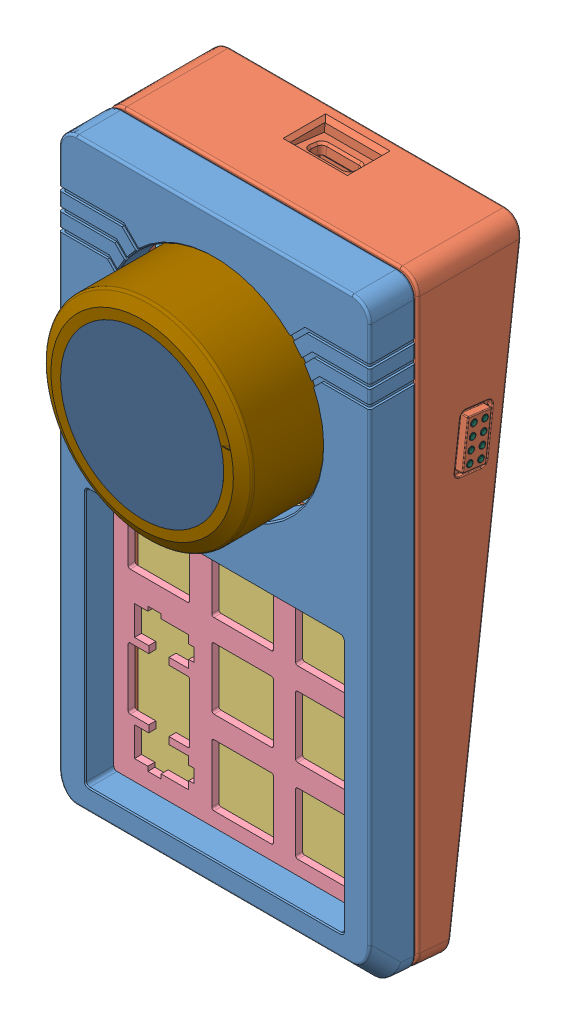
SolidWorks assembly 00-装配体 旋钮扩展, configuration 默认. Lengths in mm.
Overall size (76.26 142.75 71.45).
19 component instances, 17 part files, 22 mates.
Components (placement in the parent):
- 01 零件 旋钮扩展上盖-1: 01 零件 旋钮扩展上盖 [默认] at origin size (70.5 136.95 11.4)
- 02-零件 旋钮扩展底壳-1: 02-零件 旋钮扩展底壳 [默认] at (70.5 1.7565 0) x (-1 0 0) z (0 0 -1) size (72.2 137.62 26.75)
- 04-零件 旋钮扩展按键PCB板-1: 04-零件 旋钮扩展按键PCB板 [默认] at (34.7996 31.8269 -1.2) size (57.5 71.01 1.2)
- 03-零件 旋钮扩展定位板-1: 03-零件 旋钮扩展定位板 [默认] at (15.5008 11.1842 3.4) x (1 0 0) z (0 -1 0) size (64.5 1.6 69.5)
- 00-装配体 旋钮部分-1: 00-装配体 旋钮部分 [默认] at (35.25 104 -1.2) x (-1 0 0) z (0 1 0) size (76.26 54.3 76.26)
  - 01-零件 PCB板-1: 01-零件 PCB板 [默认] at origin size (50 1 50)
  - 02-零件 电机底座-1: 02-零件 电机底座 [默认] at (0 6.2 0) size (46.19 23 52.91)
  - 03-零件 电机-1: 03-零件 电机 [默认] at (0 4.58 0) x (0 0 1) z (-1 0 0) size (47.53 47.1 35.44)
  - 04-零件 电机上罩-1: 04-零件 电机上罩 [默认] at (0 10.7 0) x (0.707107 0 0.707107) z (-0.707107 0 0.707107) size (56.5 12.14 51.36)
  - 05-零件 旋钮上外壳-1: 05-零件 旋钮上外壳 [默认] at (0 2.8 0) x (0.965926 0 -0.258819) z (0.258819 0 0.965926) size (47 26.2 47)
  - 06-零件 旋钮玻璃-1: 06-零件 旋钮玻璃 [默认] at (0 28 0) size (37 1 37)
  - 07-零件 6x6x5轻触开关-1: 07-零件 6x6x5轻触开关 [默认] at (0 0 -10) x (-1 0 0) z (0 0 1) size (6 5 6)
  - 零件 TFTLCD支撑圈-1: 零件 TFTLCD支撑圈 [默认] at (0 19 0) size (11.21 5.4 12)
  - 零件 PCB-TFTLCD-1: 零件 PCB-TFTLCD [默认] at (0 24 0) x (1 0 0) z (0 1 0) size (38.77 35.97 1)
  - 零件 TFT LCD 1.28inch-1: 零件 TFT LCD 1.28inch [默认] at (0 25.3 0) size (38.6 1.9 35.6)
- 08-Q零件 顶针2x4pin 母座-1: 08-Q零件 顶针2x4pin 母座 [默认] at (68.9 94.1579 -9.0911) x (0 0.992546 -0.121869) z (0 0.121869 0.992546) size (10.2 6.8 5)
- 09-Q零件 顶针2x4pin 公头-1: 09-Q零件 顶针2x4pin 公头 [默认] at (1.7 104.2819 -10.3341) x (0 -0.992546 0.121869) z (0 0.121869 0.992546) size (10.2 6.85 5)
- 06-Q零件 磁铁 20x3-1: 06-Q零件 磁铁 20x3 [默认] at (4 118.4896 -10.0636) x (0 0 1) z (-1 0 0) size (20 20 3)
- 06-Q零件 磁铁 20x3-2: 06-Q零件 磁铁 20x3 [默认] at (66.5 118.4896 -10.0636) x (0 0 -1) z (1 0 0) size (20 20 3)
Mates (geometry in assembly coordinates):
- 重合28: coincident anti-aligned: plane of 01 零件 旋钮扩展上盖-1 through (70.5 0 0) normal (0 0 -1); plane of 02-零件 旋钮扩展底壳-1 through (70.5 1.7565 0) normal (0 0 1)
- 重合29: coincident aligned: plane of 01 零件 旋钮扩展上盖-1 through (70.5 137 0) normal (0 1 0); plane of 02-零件 旋钮扩展底壳-1 through (0 137 0) normal (0 1 0)
- 重合30: coincident aligned: plane of 01 零件 旋钮扩展上盖-1 through (0 0 0) normal (-1 0 0); plane of 02-零件 旋钮扩展底壳-1 through (0 1.7565 0) normal (-1 0 0)
- 重合35: coincident anti-aligned: plane of 02-零件 旋钮扩展底壳-1 through (70.5 1.7565 -1.2) normal (0 0 1); plane of 04-零件 旋钮扩展按键PCB板-1 through (34.7996 31.8269 -1.2) normal (0 0 -1)
- 距离2: distance = 0.5 mm anti-aligned: plane of 02-零件 旋钮扩展底壳-1 through (6 1.7565 -151.4076) normal (1 0 0); plane of 04-零件 旋钮扩展按键PCB板-1 through (6.5 72.4203 0) normal (-1 0 0)
- 距离3: distance = 0.5 mm anti-aligned: plane of 02-零件 旋钮扩展底壳-1 through (70.5 5.9125 -151.4076) normal (0 1 0); plane of 04-零件 旋钮扩展按键PCB板-1 through (6.5 6.4125 0) normal (0 -1 0)
- 重合41: coincident anti-aligned: plane of 02-零件 旋钮扩展底壳-1 through (66.35 129.2 3.4) normal (0 0 1); plane of 03-零件 旋钮扩展定位板-1 through (4.15 7.7125 3.4) normal (0 0 -1)
- 重合42: coincident aligned: line of 02-零件 旋钮扩展底壳-1 through (3 70.8831 3.4) axis (0 -1 0); line of 03-零件 旋钮扩展定位板-1 through (3 71.9125 3.4) axis (0 -1 0)
- 重合43: coincident aligned: line of 02-零件 旋钮扩展底壳-1 through (7.8 2.9125 3.4) axis (1 0 0); line of 03-零件 旋钮扩展定位板-1 through (7.8 2.9125 3.4) axis (1 0 0)
- 重合44: coincident anti-aligned: plane of 02-零件 旋钮扩展底壳-1 through (70.5 1.7565 -1.2) normal (0 0 1); plane of 00-装配体 旋钮部分-1/01-零件 PCB板-1 through (35.25 104 -1.2) normal (0 0 -1)
- 同心1: concentric anti-aligned: circle of 01 零件 旋钮扩展上盖-1; circle of 00-装配体 旋钮部分-1/05-零件 旋钮上外壳-1
- 平行1: parallel: plane of 02-零件 旋钮扩展底壳-1 through (70.5 131 -151.4076) normal (0 -1 0); line of 00-装配体 旋钮部分-1/01-零件 PCB板-1 through (60.25 129 -0.2) axis (-1 0 0)
- 重合51: coincident anti-aligned: plane of 02-零件 旋钮扩展底壳-1 through (68.9 1.7565 0) normal (-1 0 0); plane of 08-Q零件 顶针2x4pin 母座-1 through (68.9 94.1579 -9.0911) normal (1 0 0)
- 同心2: concentric aligned: circle of 02-零件 旋钮扩展底壳-1; circle of 08-Q零件 顶针2x4pin 母座-1
- 同心3: concentric aligned: circle of 02-零件 旋钮扩展底壳-1; circle of 08-Q零件 顶针2x4pin 母座-1
- 重合52: coincident anti-aligned: plane of 02-零件 旋钮扩展底壳-1 through (1.7 1.7565 0) normal (1 0 0); plane of 09-Q零件 顶针2x4pin 公头-1 through (1.7 104.2819 -10.3341) normal (-1 0 0)
- 同心4: concentric aligned: circle of 02-零件 旋钮扩展底壳-1; circle of 09-Q零件 顶针2x4pin 公头-1
- 同心5: concentric aligned: circle of 02-零件 旋钮扩展底壳-1; circle of 09-Q零件 顶针2x4pin 公头-1
- 重合53: coincident anti-aligned: plane of 02-零件 旋钮扩展底壳-1 through (69.5 118.4896 -10.0636) normal (-1 0 0); plane of 06-Q零件 磁铁 20x3-2 through (69.5 118.4896 -10.0636) normal (1 0 0)
- 同心6: concentric aligned: circle of 02-零件 旋钮扩展底壳-1; circle of 06-Q零件 磁铁 20x3-2
- 重合54: coincident anti-aligned: plane of 02-零件 旋钮扩展底壳-1 through (1 118.4896 -10.0636) normal (1 0 0); plane of 06-Q零件 磁铁 20x3-1 through (1 118.4896 -10.0636) normal (-1 0 0)
- 同心7: concentric aligned: circle of 02-零件 旋钮扩展底壳-1; circle of 06-Q零件 磁铁 20x3-1
